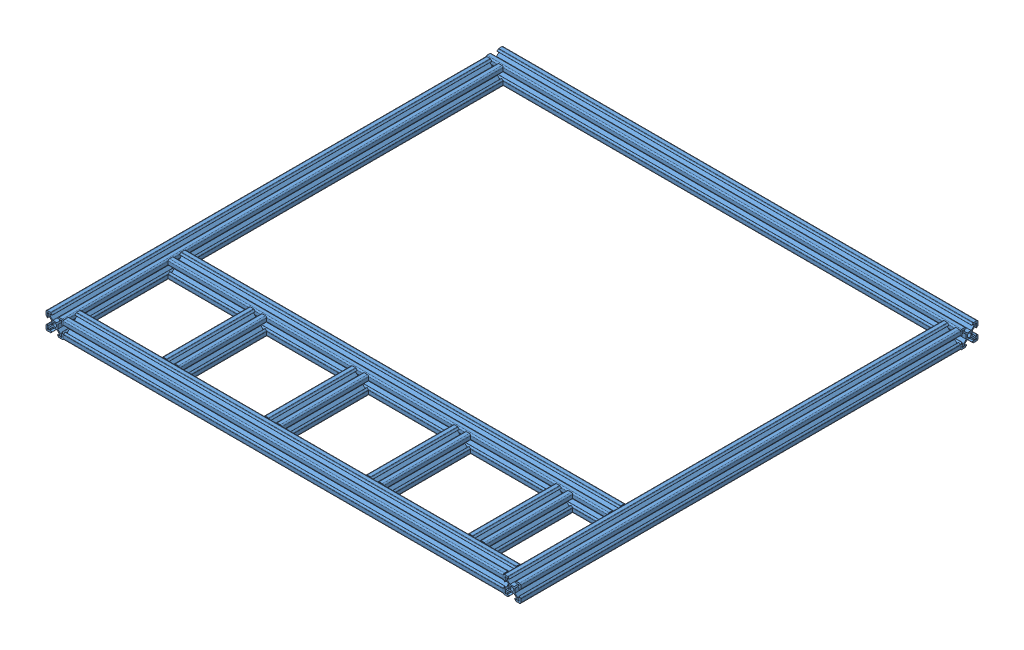
SolidWorks assembly Stack_platform, configuration Default. Lengths in mm.
Overall size (540 20 520).
9 component instances, 1 part files, 27 mates.
Components (placement in the parent):
- V-Slot 20mm x 20mm x 1000mm-1: V-Slot 20mm x 20mm x 1000mm [500] at (23.356 361.5488 651.593) size (20 20 500)
- V-Slot 20mm x 20mm x 1000mm-2: V-Slot 20mm x 20mm x 1000mm [500] at (543.356 361.5488 651.593) size (20 20 500)
- V-Slot 20mm x 20mm x 1000mm-4: V-Slot 20mm x 20mm x 1000mm [540] at (553.356 361.5488 141.593) x (0 0 -1) z (1 0 0) size (20 20 540)
- V-Slot 20mm x 20mm x 1000mm-5: V-Slot 20mm x 20mm x 1000mm [500] at (533.356 361.5488 522.593) x (0 0 -1) z (1 0 0) size (20 20 500)
- V-Slot 20mm x 20mm x 1000mm-6: V-Slot 20mm x 20mm x 1000mm [500] at (533.356 361.5488 641.593) x (0 0 -1) z (1 0 0) size (20 20 500)
- V-Slot 20mm x 20mm x 1000mm-7: V-Slot 20mm x 20mm x 1000mm [99] at (367.356 361.5488 631.593) size (20 20 99)
- V-Slot 20mm x 20mm x 1000mm-8: V-Slot 20mm x 20mm x 1000mm [99] at (483.356 361.5488 631.593) size (20 20 99)
- V-Slot 20mm x 20mm x 1000mm-9: V-Slot 20mm x 20mm x 1000mm [99] at (251.356 361.5488 631.593) size (20 20 99)
- V-Slot 20mm x 20mm x 1000mm-10: V-Slot 20mm x 20mm x 1000mm [99] at (135.356 361.5488 631.593) size (20 20 99)
Mates (geometry in assembly coordinates):
- Coincident7: coincident anti-aligned: plane of V-Slot 20mm x 20mm x 1000mm-4 through (13.356 356.6416 151.593) normal (0 0 1); plane of V-Slot 20mm x 20mm x 1000mm-1 through (14.146 356.6416 151.593) normal (0 0 -1)
- Coincident8: coincident anti-aligned: plane of V-Slot 20mm x 20mm x 1000mm-4 through (13.356 356.6416 151.593) normal (0 0 1); plane of V-Slot 20mm x 20mm x 1000mm-2 through (534.146 356.6416 151.593) normal (0 0 -1)
- Coincident9: coincident aligned: plane of V-Slot 20mm x 20mm x 1000mm-4 through (13.356 371.5488 146.5002) normal (0 1 0); plane of V-Slot 20mm x 20mm x 1000mm-2 through (538.4488 371.5488 151.593) normal (0 1 0)
- Coincident10: coincident aligned: plane of V-Slot 20mm x 20mm x 1000mm-4 through (13.356 371.5488 146.5002) normal (0 1 0); plane of V-Slot 20mm x 20mm x 1000mm-1 through (28.2633 371.5488 151.593) normal (0 1 0)
- Coincident13: coincident aligned: plane of V-Slot 20mm x 20mm x 1000mm-1 through (13.356 366.4561 151.593) normal (-1 0 0); plane of V-Slot 20mm x 20mm x 1000mm-4 through (13.356 356.6416 150.803) normal (-1 0 0)
- Coincident14: coincident aligned: plane of V-Slot 20mm x 20mm x 1000mm-1 through (28.2633 371.5488 151.593) normal (0 1 0); plane of V-Slot 20mm x 20mm x 1000mm-5 through (33.356 371.5488 527.5002) normal (0 1 0)
- Coincident15: coincident anti-aligned: plane of V-Slot 20mm x 20mm x 1000mm-1 through (33.356 366.4561 151.593) normal (1 0 0); plane of V-Slot 20mm x 20mm x 1000mm-5 through (33.356 356.6416 531.803) normal (-1 0 0)
- Coincident17: coincident aligned: plane of V-Slot 20mm x 20mm x 1000mm-1 through (28.2633 371.5488 151.593) normal (0 1 0); plane of V-Slot 20mm x 20mm x 1000mm-6 through (33.356 371.5488 636.6857) normal (0 1 0)
- Coincident19: coincident anti-aligned: plane of V-Slot 20mm x 20mm x 1000mm-6 through (33.356 366.4561 631.593) normal (0 0 -1); plane of V-Slot 20mm x 20mm x 1000mm-7 through (358.146 356.6416 631.593) normal (0 0 1)
- Coincident20: coincident anti-aligned: plane of V-Slot 20mm x 20mm x 1000mm-6 through (33.356 366.4561 631.593) normal (0 0 -1); plane of V-Slot 20mm x 20mm x 1000mm-10 through (126.146 356.6416 631.593) normal (0 0 1)
- Coincident21: coincident anti-aligned: plane of V-Slot 20mm x 20mm x 1000mm-6 through (33.356 366.4561 631.593) normal (0 0 -1); plane of V-Slot 20mm x 20mm x 1000mm-8 through (474.146 356.6416 631.593) normal (0 0 1)
- Coincident22: coincident anti-aligned: plane of V-Slot 20mm x 20mm x 1000mm-6 through (33.356 366.4561 631.593) normal (0 0 -1); plane of V-Slot 20mm x 20mm x 1000mm-9 through (242.146 356.6416 631.593) normal (0 0 1)
- Coincident23: coincident aligned: plane of V-Slot 20mm x 20mm x 1000mm-6 through (33.356 371.5488 636.6857) normal (0 1 0); plane of V-Slot 20mm x 20mm x 1000mm-8 through (478.4488 371.5488 532.593) normal (0 1 0)
- Coincident24: coincident aligned: plane of V-Slot 20mm x 20mm x 1000mm-6 through (33.356 371.5488 636.6857) normal (0 1 0); plane of V-Slot 20mm x 20mm x 1000mm-9 through (246.4488 371.5488 532.593) normal (0 1 0)
- Coincident25: coincident aligned: plane of V-Slot 20mm x 20mm x 1000mm-6 through (33.356 371.5488 636.6857) normal (0 1 0); plane of V-Slot 20mm x 20mm x 1000mm-10 through (130.4488 371.5488 532.593) normal (0 1 0)
- Coincident26: coincident aligned: plane of V-Slot 20mm x 20mm x 1000mm-6 through (33.356 371.5488 636.6857) normal (0 1 0); plane of V-Slot 20mm x 20mm x 1000mm-7 through (362.4488 371.5488 532.593) normal (0 1 0)
- Distance3: distance = 96 mm anti-aligned: plane of V-Slot 20mm x 20mm x 1000mm-8 through (473.356 366.4561 532.593) normal (-1 0 0); plane of V-Slot 20mm x 20mm x 1000mm-7 through (377.356 366.4561 532.593) normal (1 0 0)
- Distance4: distance = 96 mm anti-aligned: plane of V-Slot 20mm x 20mm x 1000mm-9 through (261.356 366.4561 532.593) normal (1 0 0); plane of V-Slot 20mm x 20mm x 1000mm-7 through (357.356 366.4561 532.593) normal (-1 0 0)
- Distance7: distance = 60 mm aligned: plane of V-Slot 20mm x 20mm x 1000mm-8 through (473.356 366.4561 532.593) normal (-1 0 0); plane of V-Slot 20mm x 20mm x 1000mm-2 through (533.356 366.4561 151.593) normal (-1 0 0)
- Distance8: distance = 96 mm anti-aligned: plane of V-Slot 20mm x 20mm x 1000mm-9 through (241.356 366.4561 532.593) normal (-1 0 0); plane of V-Slot 20mm x 20mm x 1000mm-10 through (145.356 366.4561 532.593) normal (1 0 0)
- Coincident27: coincident anti-aligned: plane of V-Slot 20mm x 20mm x 1000mm-1 through (33.356 366.4561 151.593) normal (1 0 0); plane of V-Slot 20mm x 20mm x 1000mm-6 through (33.356 356.6416 650.803) normal (-1 0 0)
- Coincident28: coincident aligned: plane of V-Slot 20mm x 20mm x 1000mm-1 through (14.146 356.6416 651.593) normal (0 0 1); plane of V-Slot 20mm x 20mm x 1000mm-6 through (33.356 366.4561 651.593) normal (0 0 1)
- Coincident29: coincident aligned: plane of V-Slot 20mm x 20mm x 1000mm-10 through (126.146 356.6416 532.593) normal (0 0 -1); plane of V-Slot 20mm x 20mm x 1000mm-9 through (242.146 356.6416 532.593) normal (0 0 -1)
- Coincident30: coincident aligned: plane of V-Slot 20mm x 20mm x 1000mm-10 through (126.146 356.6416 532.593) normal (0 0 -1); plane of V-Slot 20mm x 20mm x 1000mm-7 through (358.146 356.6416 532.593) normal (0 0 -1)
- Coincident31: coincident aligned: plane of V-Slot 20mm x 20mm x 1000mm-10 through (126.146 356.6416 532.593) normal (0 0 -1); plane of V-Slot 20mm x 20mm x 1000mm-8 through (474.146 356.6416 532.593) normal (0 0 -1)
- Coincident32: coincident anti-aligned: plane of V-Slot 20mm x 20mm x 1000mm-5 through (33.356 366.4561 532.593) normal (0 0 1); plane of V-Slot 20mm x 20mm x 1000mm-10 through (126.146 356.6416 532.593) normal (0 0 -1)
- Coincident33: coincident anti-aligned: plane of V-Slot 20mm x 20mm x 1000mm-2 through (533.356 366.4561 151.593) normal (-1 0 0); plane of V-Slot 20mm x 20mm x 1000mm-6 through (533.356 356.6416 650.803) normal (1 0 0)
